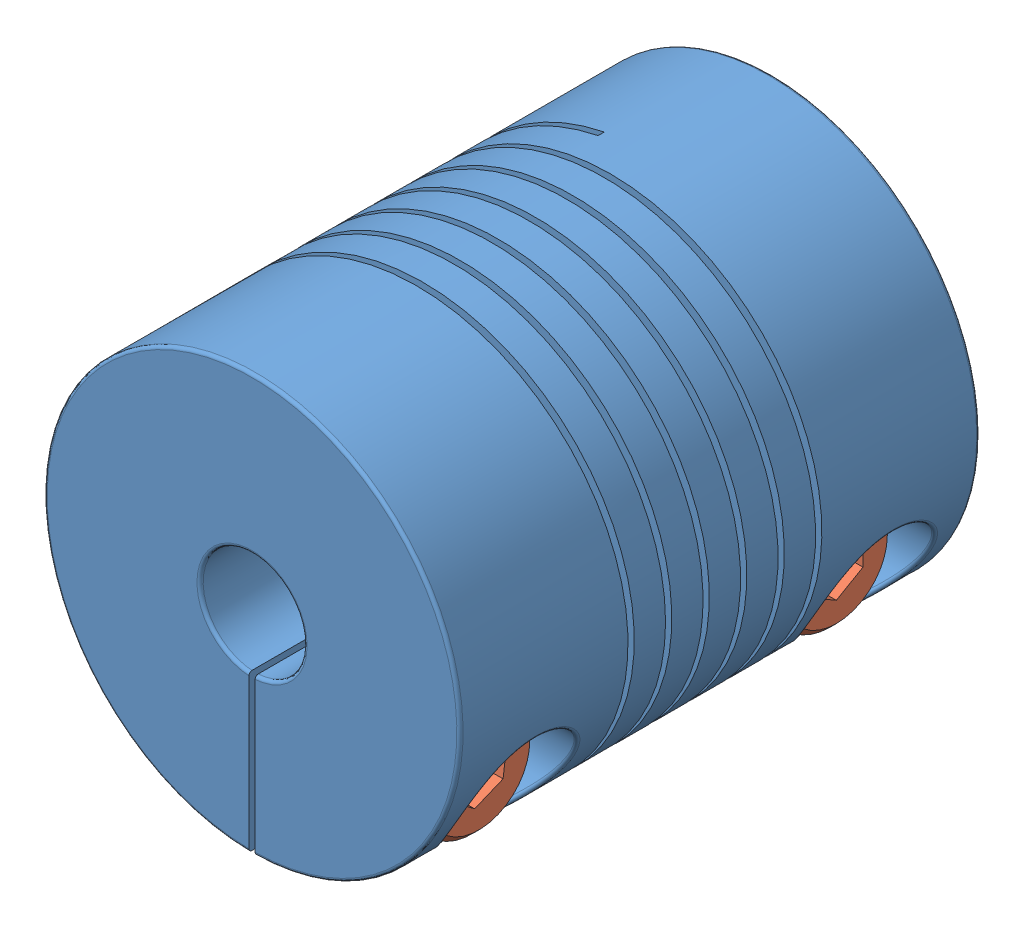
SolidWorks assembly 5mm x 8mm Flexible Coupling, configuration Default. Lengths in mm.
Overall size (20.7 20.83 25.02).
3 component instances, 2 part files, 4 mates.
Components (placement in the parent):
- 5mm x 8mm Flexible Coupling-1: 5mm x 8mm Flexible Coupling [Default] at (-34.9739 -2.4531 32.6221) size (20.7 20.83 25.02)
- Socket Head Cap Screw_AM-1: Socket Head Cap Screw_AM [B18.3.1M - 3 x 0.5 x 12 Hex SHCS -- 12NHX] at (-27.9739 -7.4531 28.7221) x (-1 0 0) z (0 -0.924225 -0.381849) size (15 5.5 5.5)
- Socket Head Cap Screw_AM-2: Socket Head Cap Screw_AM [B18.3.1M - 3 x 0.5 x 12 Hex SHCS -- 12NHX] at (-27.9739 -7.4531 11.5221) x (-1 0 0) z (0 0 -1) size (15 5.5 5.5)
Mates (geometry in assembly coordinates):
- Coincident1: coincident anti-aligned: plane of 5mm x 8mm Flexible Coupling-1 through (-30.9739 -7.4531 28.7221) normal (1 0 0); plane of Socket Head Cap Screw_AM-1 through (-30.9739 -6.403 26.1805) normal (-1 0 0)
- Coincident2: coincident aligned: circle of 5mm x 8mm Flexible Coupling-1; circle of Socket Head Cap Screw_AM-1
- Coincident3: coincident anti-aligned: plane of 5mm x 8mm Flexible Coupling-1 through (-30.9739 -7.4531 11.5221) normal (1 0 0); plane of Socket Head Cap Screw_AM-2 through (-30.9739 -4.7031 11.5221) normal (-1 0 0)
- Concentric1: concentric aligned: cylinder of 5mm x 8mm Flexible Coupling-1 through (-45.3254 -7.4531 11.5221) axis (1 0 0) radius 1.5; cylinder of Socket Head Cap Screw_AM-2 through (3.7761 -7.4531 11.5221) axis (1 0 0) radius 1.5
